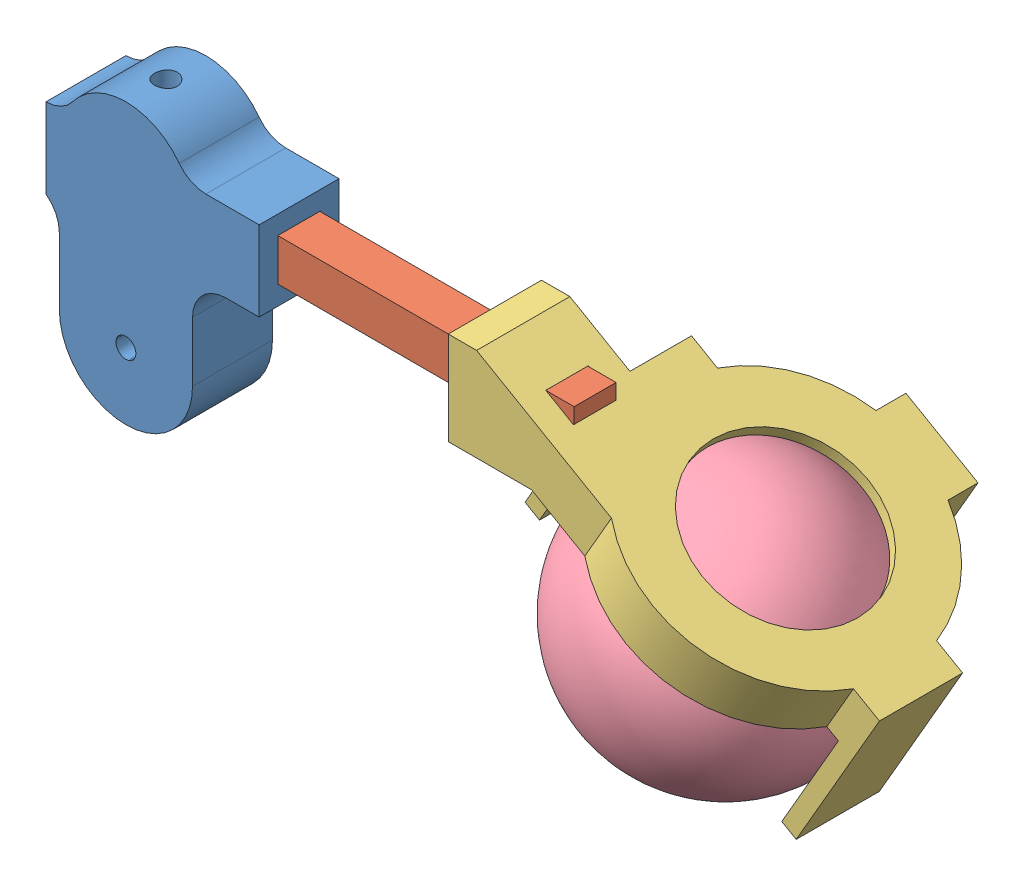
SolidWorks assembly 02 Arm Assembly, configuration Default. Lengths in mm.
Overall size (115.48 57.45 43.5).
4 component instances, 4 part files, 16 mates.
Components (placement in the parent):
- Arm-Servo Mount-1: Arm-Servo Mount [Default] at origin size (32 42 12)
- Arm Rod-1: Arm Rod [Default] at (0 20.05 6.05) x (0 -1 0) z (0 0 1) size (6.3 64.5 6.3)
- Arm Hoop-1: Arm Hoop [Default] at (83.1311 10.1413 -3.9) x (0 0 -1) z (-0.5 -0.866025 0) size (43.5 61.1 25)
- SquashBall-1: SquashBall [Default] at (74.1311 -5.4471 -3.9) size (40 40 40)
Mates (geometry in assembly coordinates):
- Coincident1: coincident: line of Arm-Servo Mount-1 through (0 0 0) axis (0 0 1); plane of assembly
- Coincident2: coincident: line of Arm-Servo Mount-1 through (0 0 0) axis (0 0 1); plane of assembly
- Coincident3: coincident aligned: plane of Arm-Servo Mount-1 through (0 0 0) normal (1 0 0); plane of assembly through (0 0 0) normal (1 0 0)
- Coincident6: coincident anti-aligned: plane of Arm Rod-1 through (64.5 20.05 6.05) normal (1 0 0); plane of Arm Hoop-1 through (64.5 25.05 6.05) normal (-1 0 0)
- Coincident9: coincident anti-aligned: line of Arm Rod-1 through (64.5 23.2 9.2) axis (0 -1 0); line of Arm Hoop-1 through (64.5 16.9 9.2) axis (0 1 0)
- Coincident12: coincident: plane of Arm Rod-1 through (64.5 16.9 2.9) normal (0 -1 0); line of Arm Hoop-1 through (52.5 16.9 2.9) axis (0 0 1)
- Coincident13: coincident aligned: plane of Arm-Servo Mount-1 through (0 0 0) normal (0 0 1); plane of assembly through (0 0 0) normal (0 0 1)
- Concentric1: concentric: sphere of Arm Hoop-1; sphere of SquashBall-1
- Coincident16: coincident anti-aligned: plane of Arm-Servo Mount-1 through (-12 23.2 9.2) normal (0 -1 0); plane of Arm Rod-1 through (64.5 23.2 2.9) normal (0 1 0)
- Coincident17: coincident anti-aligned: plane of Arm-Servo Mount-1 through (-12 23.2 9.2) normal (0 0 -1); plane of Arm Rod-1 through (64.5 23.2 9.2) normal (0 0 1)
- Coincident18: coincident anti-aligned: plane of Arm-Servo Mount-1 through (0 0 0) normal (1 0 0); plane of Arm Rod-1 through (0 20.05 6.05) normal (-1 0 0)
- Parallel1: parallel aligned: plane of SquashBall-1 through (88.5593 13.2526 -1.314) normal (0 1 0); plane of assembly through (0 0 0) normal (0 1 0)
- Parallel2: parallel aligned: plane of SquashBall-1 through (88.5593 13.2526 -1.314) normal (1 0 0); plane of assembly through (0 0 0) normal (1 0 0)
- Parallel3: parallel aligned: plane of SquashBall-1 through (88.5593 13.2526 -1.314) normal (0 0 1); plane of assembly through (0 0 0) normal (0 0 1)
- Coincident19: coincident anti-aligned: line of Arm Rod-1 through (64.5 16.9 9.2) axis (0 0 -1); line of Arm Hoop-1 through (64.5 16.9 2.9) axis (0 0 1)
- Coincident20: coincident anti-aligned: line of Arm Rod-1 through (64.5 16.9 2.9) axis (0 1 0); line of Arm Hoop-1 through (64.5 20.898 2.9) axis (0 -1 0)
